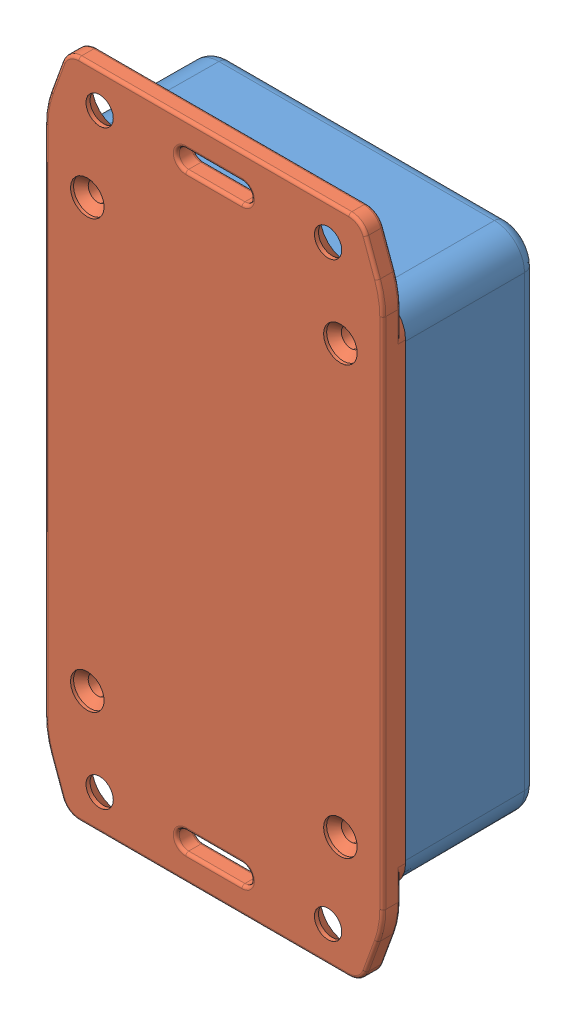
SolidWorks assembly 1591MFLGY, configuration Default. Lengths in mm.
Overall size (56.2 110 25.82).
11 component instances, 5 part files, 11 mates.
Components (placement in the parent):
- 1591M Box-1: 1591M Box [Default] at (-2.1795 -0.0468 0) size (56 84.8 22.02)
- 1591L-M Flange Lid-1: 1591L-M Flange Lid [Default] at (-2.1295 0.0032 0) x (0 -1 0) z (0 0 -1) size (110 56.2 6.5)
- SC500 (screw M3-0.5X 10mm FH)-1: SC500 (screw M3-0.5X 10mm FH) [Default] at (-21.05 35.55 2.05) x (1 0 0) z (0 -1 0) (suppressed, hidden)
- SC500 (screw M3-0.5X 10mm FH)-2: SC500 (screw M3-0.5X 10mm FH) [Default] at (21.05 35.55 2.05) x (1 0 0) z (0 -1 0) (suppressed, hidden)
- SC500 (screw M3-0.5X 10mm FH)-3: SC500 (screw M3-0.5X 10mm FH) [Default] at (-21.05 -35.55 2.05) x (1 0 0) z (0 -1 0) (suppressed, hidden)
- SC500 (screw M3-0.5X 10mm FH)-4: SC500 (screw M3-0.5X 10mm FH) [Default] at (21.05 -35.55 2.05) x (1 0 0) z (0 -1 0) (suppressed, hidden)
- IN100 (insert M3-0.5X5.75mm BRASS)-1: IN100 (insert M3-0.5X5.75mm BRASS) [Default] at (-23.2795 -35.6468 -8.965) x (1 0 0) z (0 -1 0) size (4.83 5.72 4.83)
- IN100 (insert M3-0.5X5.75mm BRASS)-2: IN100 (insert M3-0.5X5.75mm BRASS) [Default] at (18.9205 -35.6468 -8.965) x (1 0 0) z (0 -1 0) size (4.83 5.72 4.83)
- IN100 (insert M3-0.5X5.75mm BRASS)-3: IN100 (insert M3-0.5X5.75mm BRASS) [Default] at (18.9205 35.5532 -8.965) x (1 0 0) z (0 -1 0) size (4.83 5.72 4.83)
- IN100 (insert M3-0.5X5.75mm BRASS)-4: IN100 (insert M3-0.5X5.75mm BRASS) [Default] at (-23.2795 35.5532 -8.965) x (1 0 0) z (0 -1 0) size (4.83 5.72 4.83)
- PCB-2: PCB [Default] at (-1.7972 -0.1941 -2.7) x (0.999988 0.004989 0) z (-0.004989 0.999988 0) size (44.45 1.59 63.5)
Mates (geometry in assembly coordinates):
- Coincident3: coincident aligned: plane of 1591M Box-1 through (-23.2795 -35.6468 -3.25) normal (0 0 1); plane of IN100 (insert M3-0.5X5.75mm BRASS)-1 through (-22.073 -35.6468 -3.25) normal (0 0 1)
- Concentric4: concentric anti-aligned: cylinder of 1591M Box-1 through (-23.2795 -35.6468 -3.25) axis (0 0 1) radius 1.994; circle of IN100 (insert M3-0.5X5.75mm BRASS)-1
- Concentric5: concentric anti-aligned: circle of 1591M Box-1; circle of IN100 (insert M3-0.5X5.75mm BRASS)-4
- Coincident5: coincident aligned: plane of 1591M Box-1 through (-23.2795 35.5532 -3.25) normal (0 0 1); plane of IN100 (insert M3-0.5X5.75mm BRASS)-4 through (-22.073 35.5532 -3.25) normal (0 0 1)
- Coincident6: coincident aligned: plane of 1591M Box-1 through (18.9205 35.5532 -3.25) normal (0 0 1); plane of IN100 (insert M3-0.5X5.75mm BRASS)-3 through (20.127 35.5532 -3.25) normal (0 0 1)
- Concentric6: concentric aligned: circle of 1591M Box-1; circle of IN100 (insert M3-0.5X5.75mm BRASS)-3
- Coincident7: coincident aligned: plane of 1591M Box-1 through (18.9205 -35.6468 -3.25) normal (0 0 1); plane of IN100 (insert M3-0.5X5.75mm BRASS)-2 through (20.127 -35.6468 -3.25) normal (0 0 1)
- Concentric7: concentric aligned: circle of 1591M Box-1; circle of IN100 (insert M3-0.5X5.75mm BRASS)-2
- Concentric8: concentric anti-aligned: cylinder of 1591L-M Flange Lid-1 through (18.9205 35.5532 -0.7) axis (0 0 1) radius 1.6; circle of IN100 (insert M3-0.5X5.75mm BRASS)-3
- Coincident8: coincident anti-aligned: plane of 1591M Box-1 through (-2.1795 -0.0468 0) normal (0 0 1); plane of 1591L-M Flange Lid-1 through (-2.1295 0.0032 0) normal (0 0 -1)
- Coincident10: coincident anti-aligned: plane of 1591L-M Flange Lid-1 through (-19.8795 28.0032 -2.7) normal (0 0 -1); plane of PCB-2 through (-22.5849 29.865 -2.7) normal (0 0 1)
